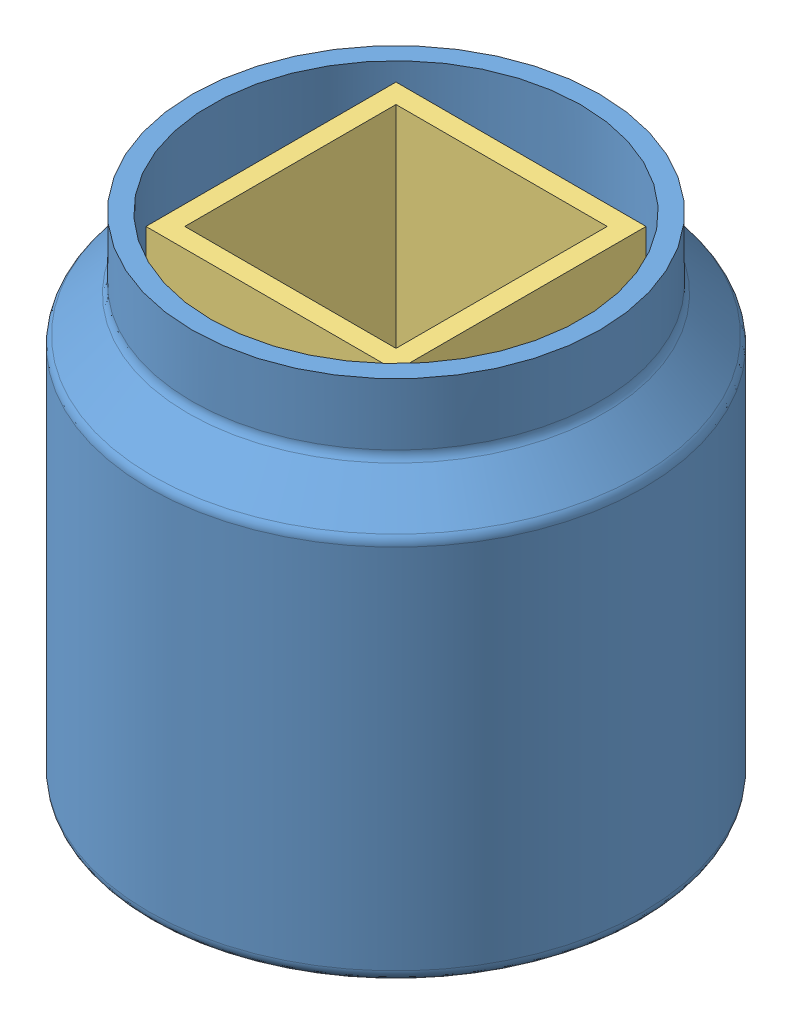
SolidWorks assembly Setup, configuration Défaut. Lengths in mm.
Overall size (80 80 80).
5 component instances, 5 part files, 5 mates.
Components (placement in the parent):
- Jar-2: Jar [Défaut] at origin size (80 80 80)
- InitialFill-1: InitialFill [Défaut] at origin size (74 10 74)
- Prototype-1: Prototype [Défaut] at origin size (40.45 65 40.45) (hidden)
- Bone-1: Bone [Défaut] at origin size (45 3 45)
- FinalFill-1: FinalFill [Défaut] at origin size (74 20 74)
Mates (geometry in assembly coordinates):
- Coïncidente4: coordinate: point of assembly; point of Jar-2; point of assembly
- Coïncidente8: coordinate: point of Jar-2; point of InitialFill^Setup-1
- Coïncidente10: coordinate: point of Jar-2; point of Prototype^Setup-1
- Coïncidente12: coordinate: point of Jar-2; point of Bone^Setup-1
- Coïncidente14: coordinate: unknown of FinalFill^Setup-1
